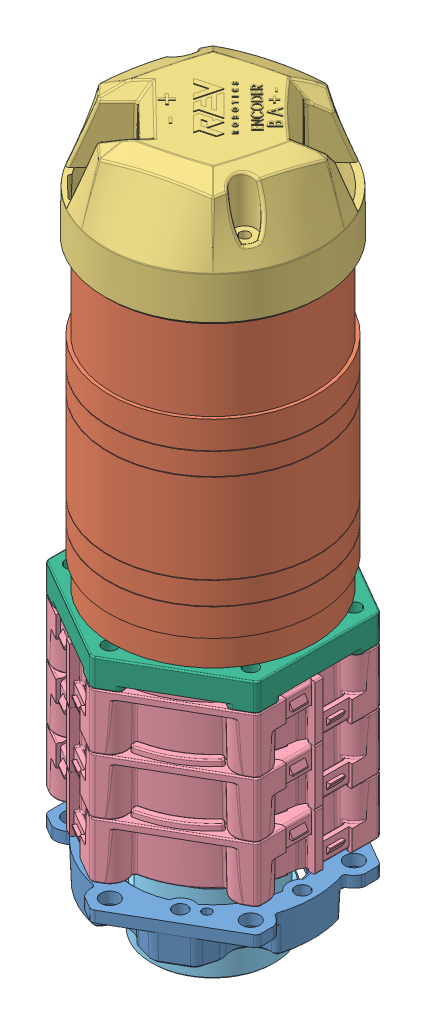
SolidWorks assembly HD HEX 3 Gear box2, configuration Valor predeterminado. Lengths in mm.
Overall size (38.85 127.43 43.57).
9 component instances, 7 part files, 0 mates.
Components (placement in the parent):
- REV-41-1615-Enc_Externo-1: REV-41-1615-Enc_Externo [Valor predeterminado] at (-0.0045 -68.4434 0.0426) x (0 0 -1) z (-1 0 0) size (43.57 7.02 38)
- REV-41-1615-Enc_Redu_X_E7ao.step-1: REV-41-1615-Enc_Redu_X_E7ao.step [Valor predeterminado] at (-0.0045 -68.4434 0.0426) x (0 0 1) z (1 0 0) (suppressed, hidden)
- Motor dummy_Without Gearbox-1: Motor dummy_Without Gearbox [Valor predeterminado] at (-0.0045 34.8066 0.0426) x (0 -1 0) z (0 0 1) size (78.7 37.3 37.3)
- HD Hex Encoder Case Top-1: HD Hex Encoder Case Top [Valor predeterminado] at (-0.0045 39.8066 0.0426) x (-1 0 0) z (0 1 0) size (38.76 38.76 20.21)
- REV-41-1601-Encaixe-1: REV-41-1601-Encaixe [Valor predeterminado] at (-0.0045 -32.1934 0.0426) x (0 0 1) z (1 0 0) size (43.57 11.07 38.75)
- REV-41-1615-Enc_Eixo-1: REV-41-1615-Enc_Eixo [Valor predeterminado] at (-0.0045 -69.4434 0.0426) x (0.640309 0 0.768118) z (0.768118 0 -0.640309) size (22 13.25 22)
- REV-41-1607-1: REV-41-1607 [Valor predeterminado] at (-0.0045 -22.1934 0.0426) x (0 0 -1) z (0 -1 0) size (43.57 38.08 5.05)
- REV-41-1601-Encaixe-2: REV-41-1601-Encaixe [Valor predeterminado] at (-0.0045 -52.1934 0.0426) x (0 0 1) z (1 0 0) size (43.57 11.07 38.75)
- REV-41-1601-Encaixe-3: REV-41-1601-Encaixe [Valor predeterminado] at (-0.0045 -42.1934 0.0426) x (0 0 1) z (1 0 0) size (43.57 11.07 38.75)
